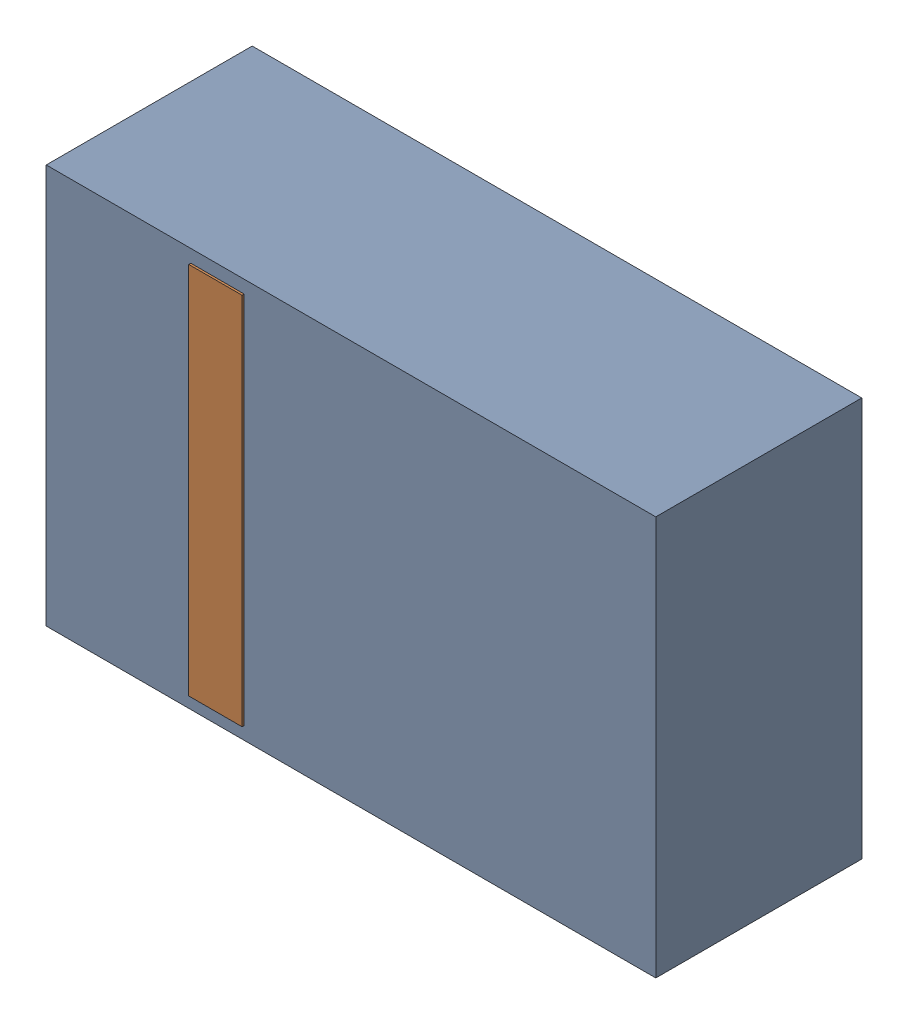
SolidWorks assembly D24, configuration Default. Lengths in mm.
Overall size (2.9 1.9 0.99).
4 component instances, 2 part files, 0 mates.
Components (placement in the parent):
- 905269392-1: 905269392 [Default] at (146.812 61.341 0) size (2.9 1.9 0.98)
  - Extruded_5-1: Extruded_5 [Default] at origin size (2.9 1.9 0.98)
- 905269800-1: 905269800 [Default] at (146.177 61.341 0.95) size (0.25 1.78 0.04)
  - Extruded_6-1: Extruded_6 [Default] at origin size (0.25 1.78 0.04)
